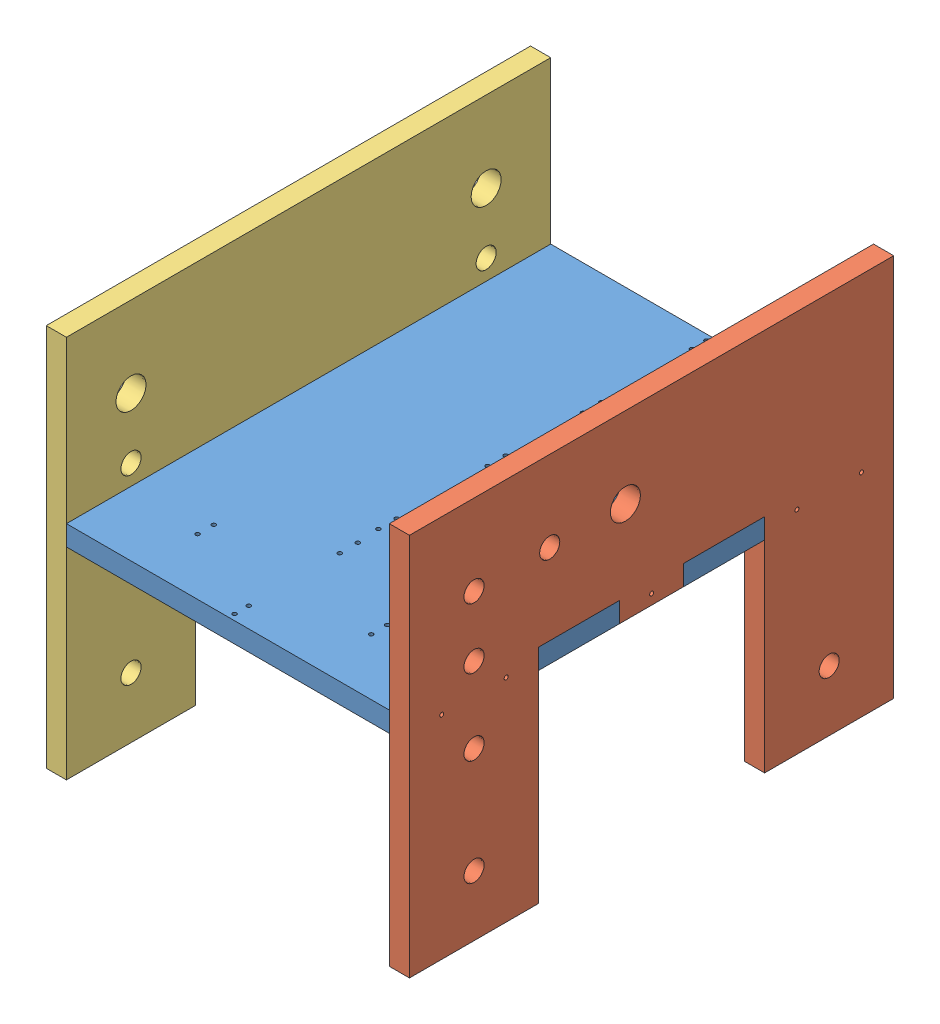
SolidWorks assembly Chassis_Assembly, configuration Default. Lengths in mm.
Overall size (114.3 120.65 152.4).
3 component instances, 3 part files, 6 mates.
Components (placement in the parent):
- Base_Plate-1: Base_Plate [Default] at (17.453 79.4472 187.1525) size (114.3 6.35 152.4)
- Side_Plate (1M)-1: Side_Plate (1M) [Default] at (119.053 15.9472 187.1525) x (0 0 -1) z (1 0 0) size (152.4 120.65 6.35)
- Side_Plate (2M)-1: Side_Plate (2M) [Default] at (11.103 15.9472 187.1525) x (0 0 -1) z (1 0 0) size (152.4 120.65 6.35)
Mates (geometry in assembly coordinates):
- Coincident1: coincident anti-aligned: plane of Base_Plate-1 through (17.453 85.7972 187.1525) normal (-1 0 0); plane of Side_Plate (2M)-1 through (17.453 15.9472 187.1525) normal (1 0 0)
- Coincident2: coincident aligned: plane of Base_Plate-1 through (17.453 85.7972 187.1525) normal (0 0 1); plane of Side_Plate (2M)-1 through (17.453 85.7972 187.1525) normal (0 0 1)
- Coincident3: coincident aligned: plane of Base_Plate-1 through (17.453 79.4472 187.1525) normal (0 -1 0); plane of Side_Plate (2M)-1 through (17.453 79.4472 146.5125) normal (0 -1 0)
- Coincident4: coincident aligned: plane of Base_Plate-1 through (17.453 79.4472 187.1525) normal (0 -1 0); plane of Side_Plate (1M)-1 through (125.403 79.4472 146.5125) normal (0 -1 0)
- Coincident5: coincident aligned: plane of Base_Plate-1 through (17.453 85.7972 187.1525) normal (0 0 1); plane of Side_Plate (1M)-1 through (125.403 85.7972 187.1525) normal (0 0 1)
- Coincident6: coincident anti-aligned: plane of Base_Plate-1 through (119.053 85.7972 187.1525) normal (1 0 0); plane of Side_Plate (1M)-1 through (119.053 15.9472 187.1525) normal (-1 0 0)
